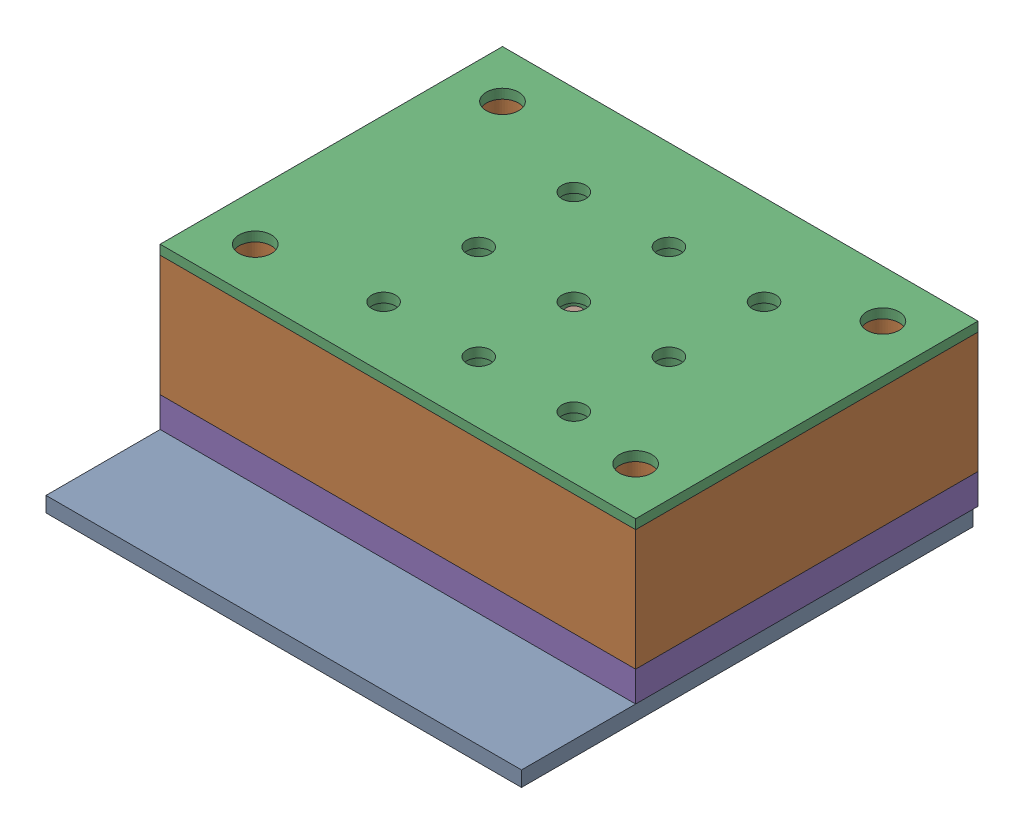
SolidWorks assembly LightTouchAssembly_3x3, configuration Default. Lengths in mm.
Overall size (50 18.48 48).
9 component instances, 9 part files, 18 mates.
Components (placement in the parent):
- PCB_3x3-1: PCB_3x3 [Default] at (598.9377 884.0262 1300.4403) size (50 1.6 47.5)
- MagnetShielding-1: MagnetShielding [Default] at (648.9377 901.5012 1288.4403) x (-1 0 0) z (0 0 1) size (50 12.7 36)
- DelrinGuide-1: DelrinGuide [Default] at (648.9377 902.5012 1288.4403) x (-1 0 0) z (0 0 1) size (50 9.53 36)
- Magnet_4mm-1: Magnet_4mm [Default] at (625.9377 894.3889 1271.9403) x (0.755958 0 -0.65462) z (0.65462 0 0.755958) size (3 4 3)
- HeatSink-1: HeatSink [Default] at (648.9377 888.8012 1288.4403) x (-1 0 0) z (0 0 1) size (50 3.17 36)
- Core_SDR0604-821KL-1: Core_SDR0604-821KL [Default] at (625.9377 885.6262 1271.9403) size (5.8 4.8 5.8)
- Coil_SDR0604-821KL-1: Coil_SDR0604-821KL [Default] at (625.9377 886.3762 1271.9403) size (4.9 3.55 4.9)
- Tactor-1: Tactor [Default] at (625.9377 898.3889 1271.9403) size (1.59 3.17 1.59)
- Elastomer-1: Elastomer [Default] at (625.9377 891.9262 1271.9403) x (-0.837169 0 -0.546944) z (-0.546944 0 0.837169) size (6 1.5 6)
Mates (geometry in assembly coordinates):
- Coincident1: coincident anti-aligned: plane of Core_SDR0604-821KL-1 through (625.9377 889.9262 1271.9403) normal (0 -1 0); plane of Coil_SDR0604-821KL-1 through (625.9377 889.9262 1271.9403) normal (0 1 0)
- Concentric1: concentric aligned: circle of Core_SDR0604-821KL-1; circle of Coil_SDR0604-821KL-1
- Concentric2: concentric aligned: circle of Magnet_4mm-1; circle of Core_SDR0604-821KL-1
- Concentric3: concentric aligned: circle of Core_SDR0604-821KL-1; circle of Tactor-1
- Concentric4: concentric aligned: circle of PCB_3x3-1; circle of Core_SDR0604-821KL-1
- Coincident2: coincident anti-aligned: plane of PCB_3x3-1 through (598.9377 885.6262 1300.4403) normal (0 1 0); plane of Core_SDR0604-821KL-1 through (625.9377 885.6262 1271.9403) normal (0 -1 0)
- Coincident3: coincident anti-aligned: plane of Core_SDR0604-821KL-1 through (625.9377 890.4262 1271.9403) normal (0 1 0); plane of Elastomer-1 through (625.9377 890.4262 1271.9403) normal (0 -1 0)
- Concentric5: concentric anti-aligned: circle of Core_SDR0604-821KL-1; circle of Elastomer-1
- Coincident14: coincident anti-aligned: plane of PCB_3x3-1 through (598.9377 885.6262 1300.4403) normal (0 1 0); plane of HeatSink-1 through (648.9377 885.6262 1288.4403) normal (0 -1 0)
- Concentric14: concentric anti-aligned: circle of PCB_3x3-1; circle of HeatSink-1
- Concentric15: concentric anti-aligned: circle of PCB_3x3-1; circle of HeatSink-1
- Coincident17: coincident anti-aligned: plane of MagnetShielding-1 through (648.9377 888.8012 1288.4403) normal (0 -1 0); plane of HeatSink-1 through (648.9377 888.8012 1288.4403) normal (0 1 0)
- Concentric16: concentric aligned: circle of MagnetShielding-1; circle of HeatSink-1
- Coincident19: coincident anti-aligned: plane of MagnetShielding-1 through (648.9377 901.5012 1288.4403) normal (0 1 0); plane of DelrinGuide-1 through (648.9377 901.5012 1288.4403) normal (0 -1 0)
- Concentric17: concentric aligned: circle of MagnetShielding-1; circle of DelrinGuide-1
- Concentric18: concentric aligned: circle of MagnetShielding-1; circle of HeatSink-1
- Concentric19: concentric aligned: circle of MagnetShielding-1; circle of DelrinGuide-1
- Coincident23: coincident anti-aligned: plane of Magnet_4mm-1 through (625.9377 898.3889 1271.9403) normal (0 1 0); plane of Tactor-1 through (625.9377 898.3889 1271.9403) normal (0 -1 0)
